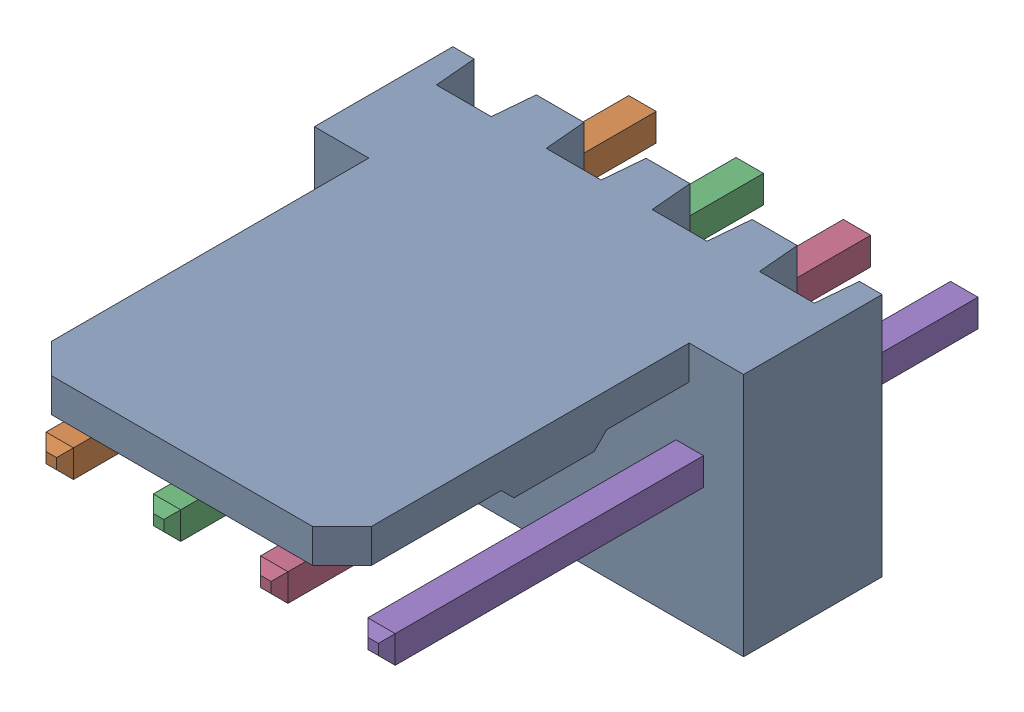
SolidWorks assembly Molex PCB 4 pin v3, configuration Default. Lengths in mm.
Overall size (10.16 5.79 14.92).
5 component instances, 2 part files, 0 mates.
Components (placement in the parent):
- BASE9710016 (2)-1: BASE9710016 (2) [Default] at (1.54 2.895 -8.22) size (10.16 5.79 11.5)
- PINO9710016 (2)-1: PINO9710016 (2) [Default] at (0.27 3.325 -0.72) size (0.65 0.65 14.2)
- PINO9710016 (2)-2: PINO9710016 (2) [Default] at (2.81 3.325 -0.72) size (0.65 0.65 14.2)
- PINO9710016 (2)-3: PINO9710016 (2) [Default] at (5.35 3.325 -0.72) size (0.65 0.65 14.2)
- PINO9710016 (2)-4: PINO9710016 (2) [Default] at (7.89 3.325 -0.72) size (0.65 0.65 14.2)
